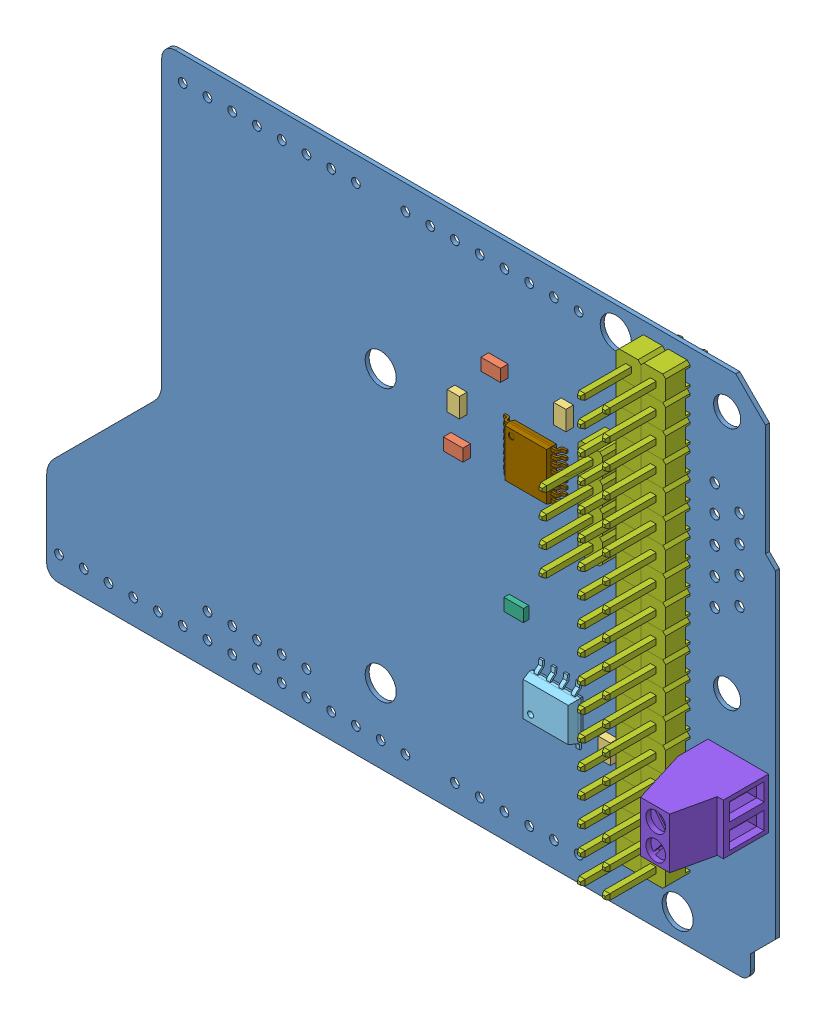
SolidWorks assembly Arduino CAN shield PCB, configuration 默认. Lengths in mm.
Overall size (74.8 53.34 11.58).
75 component instances, 9 part files, 0 mates.
Components (placement in the parent):
- Board-1: Board [默认] at (0 0 -0.4115) size (74.8 53.34 0.41)
- C1-1: C1 [默认] at origin size (2 1.25 0.78)
  - 664554168-1: 664554168 [默认] at (-19.9138 41.9098 0.0153) size (2 1.25 0.78)
    - Extruded_2-1: Extruded_2 [默认] at origin size (2 1.25 0.78)
- C2-1: C2 [默认] at origin size (1.25 2 0.78)
  - 664554032-1: 664554032 [默认] at (-23.7492 36.9318 0.0153) size (1.25 2 0.78)
    - Extruded_3-1: Extruded_3 [默认] at origin size (1.25 2 0.78)
- C3-1: C3 [默认] at origin size (1.25 2 0.78)
  - 664554032-1: 664554032 [默认] at (-12.8272 41.2498 0.0153) size (1.25 2 0.78)
    - Extruded_3-1: Extruded_3 [默认] at origin size (1.25 2 0.78)
- C4-1: C4 [默认] at origin size (2 1.25 0.78)
  - 664554304-1: 664554304 [默认] at (-21.7423 43.8149 -1.1986) size (2 1.25 0.78)
    - Extruded_4-1: Extruded_4 [默认] at origin size (2 1.25 0.78)
- C5-1: C5 [默认] at origin size (2 1.25 0.78)
  - 664554168-1: 664554168 [默认] at (-23.7742 32.8932 0.0153) size (2 1.25 0.78)
    - Extruded_2-1: Extruded_2 [默认] at origin size (2 1.25 0.78)
- C6-1: C6 [默认] at origin size (1.25 2 0.78)
  - 664554032-1: 664554032 [默认] at (-8.2548 13.8682 0.0153) size (1.25 2 0.78)
    - Extruded_3-1: Extruded_3 [默认] at origin size (1.25 2 0.78)
- CAN_1-1: CAN_1 [默认] at origin size (5.02 6.04 1.6)
  - SOP8-1: SOP8 [默认] at (-13.462 15.113 0) x (1 0 0) z (0 0 1) size (5.02 6.04 1.6)
- R1-1: R1 [默认] at origin size (2 1.26 0.55)
  - 664553896-1: 664553896 [默认] at (-17.8053 21.4885 0) size (2 1.26 0.55)
    - Extruded_5-1: Extruded_5 [默认] at origin size (2 1.26 0.55)
- GND1-1: GND1 [默认] at origin size (5.08 45.72 10.52)
  - HEADER-1: HEADER [默认] at (-2.794 49.53 0) x (0 1 0) z (1 0 0) size (2.54 10.52 2.54)
  - HEADER-2: HEADER [默认] at (-2.794 46.99 0) x (0 1 0) z (1 0 0) size (2.54 10.52 2.54)
  - HEADER-3: HEADER [默认] at (-0.254 49.53 0) x (0 1 0) z (1 0 0) size (2.54 10.52 2.54)
  - HEADER-4: HEADER [默认] at (-0.254 46.99 0) x (0 1 0) z (1 0 0) size (2.54 10.52 2.54)
  - HEADER-5: HEADER [默认] at (-2.794 44.45 0) x (0 1 0) z (1 0 0) size (2.54 10.52 2.54)
  - HEADER-6: HEADER [默认] at (-2.794 41.91 0) x (0 1 0) z (1 0 0) size (2.54 10.52 2.54)
  - HEADER-7: HEADER [默认] at (-2.794 39.37 0) x (0 1 0) z (1 0 0) size (2.54 10.52 2.54)
  - HEADER-8: HEADER [默认] at (-2.794 36.83 0) x (0 1 0) z (1 0 0) size (2.54 10.52 2.54)
  - HEADER-9: HEADER [默认] at (-0.254 44.45 0) x (0 1 0) z (1 0 0) size (2.54 10.52 2.54)
  - HEADER-10: HEADER [默认] at (-0.254 41.91 0) x (0 1 0) z (1 0 0) size (2.54 10.52 2.54)
  - HEADER-11: HEADER [默认] at (-0.254 39.37 0) x (0 1 0) z (1 0 0) size (2.54 10.52 2.54)
  - HEADER-12: HEADER [默认] at (-0.254 36.83 0) x (0 1 0) z (1 0 0) size (2.54 10.52 2.54)
  - HEADER-13: HEADER [默认] at (-2.794 34.29 0) x (0 1 0) z (1 0 0) size (2.54 10.52 2.54)
  - HEADER-14: HEADER [默认] at (-2.794 31.75 0) x (0 1 0) z (1 0 0) size (2.54 10.52 2.54)
  - HEADER-15: HEADER [默认] at (-2.794 29.21 0) x (0 1 0) z (1 0 0) size (2.54 10.52 2.54)
  - HEADER-16: HEADER [默认] at (-2.794 26.67 0) x (0 1 0) z (1 0 0) size (2.54 10.52 2.54)
  - HEADER-17: HEADER [默认] at (-0.254 34.29 0) x (0 1 0) z (1 0 0) size (2.54 10.52 2.54)
  - HEADER-18: HEADER [默认] at (-0.254 31.75 0) x (0 1 0) z (1 0 0) size (2.54 10.52 2.54)
  - HEADER-19: HEADER [默认] at (-0.254 29.21 0) x (0 1 0) z (1 0 0) size (2.54 10.52 2.54)
  - HEADER-20: HEADER [默认] at (-0.254 26.67 0) x (0 1 0) z (1 0 0) size (2.54 10.52 2.54)
  - HEADER-21: HEADER [默认] at (-2.794 24.13 0) x (0 1 0) z (1 0 0) size (2.54 10.52 2.54)
  - HEADER-22: HEADER [默认] at (-2.794 21.59 0) x (0 1 0) z (1 0 0) size (2.54 10.52 2.54)
  - HEADER-23: HEADER [默认] at (-2.794 19.05 0) x (0 1 0) z (1 0 0) size (2.54 10.52 2.54)
  - HEADER-24: HEADER [默认] at (-2.794 16.51 0) x (0 1 0) z (1 0 0) size (2.54 10.52 2.54)
  - HEADER-25: HEADER [默认] at (-0.254 24.13 0) x (0 1 0) z (1 0 0) size (2.54 10.52 2.54)
  - HEADER-26: HEADER [默认] at (-0.254 21.59 0) x (0 1 0) z (1 0 0) size (2.54 10.52 2.54)
  - HEADER-27: HEADER [默认] at (-0.254 19.05 0) x (0 1 0) z (1 0 0) size (2.54 10.52 2.54)
  - HEADER-28: HEADER [默认] at (-0.254 16.51 0) x (0 1 0) z (1 0 0) size (2.54 10.52 2.54)
  - HEADER-29: HEADER [默认] at (-2.794 13.97 0) x (0 1 0) z (1 0 0) size (2.54 10.52 2.54)
  - HEADER-30: HEADER [默认] at (-2.794 11.43 0) x (0 1 0) z (1 0 0) size (2.54 10.52 2.54)
  - HEADER-31: HEADER [默认] at (-2.794 8.89 0) x (0 1 0) z (1 0 0) size (2.54 10.52 2.54)
  - HEADER-32: HEADER [默认] at (-2.794 6.35 0) x (0 1 0) z (1 0 0) size (2.54 10.52 2.54)
  - HEADER-33: HEADER [默认] at (-0.254 13.97 0) x (0 1 0) z (1 0 0) size (2.54 10.52 2.54)
  - HEADER-34: HEADER [默认] at (-0.254 11.43 0) x (0 1 0) z (1 0 0) size (2.54 10.52 2.54)
  - HEADER-35: HEADER [默认] at (-0.254 8.89 0) x (0 1 0) z (1 0 0) size (2.54 10.52 2.54)
  - HEADER-36: HEADER [默认] at (-0.254 6.35 0) x (0 1 0) z (1 0 0) size (2.54 10.52 2.54)
- rs2322-2: rs2322 [默认] at origin size (2.54 10.16 10.52)
  - HEADER-1: HEADER [默认] at (-6.731 31.75 0) x (0 1 0) z (1 0 0) size (2.54 10.52 2.54)
  - HEADER-2: HEADER [默认] at (-6.731 34.29 0) x (0 1 0) z (1 0 0) size (2.54 10.52 2.54)
  - HEADER-3: HEADER [默认] at (-6.731 36.83 0) x (0 1 0) z (1 0 0) size (2.54 10.52 2.54)
  - HEADER-4: HEADER [默认] at (-6.731 39.37 0) x (0 1 0) z (1 0 0) size (2.54 10.52 2.54)
- CAN_bus-1: CAN_bus [默认] at origin size (6.22 5.22 10.54)
  - User_Library-Connector-2-1: User_Library-Connector-2 [默认] at (7.8106 14.224 0) x (0 1 0) z (1 0 0) size (5.22 10.54 6.22)
- RS232-1: RS232 [默认] at origin size (6.4 5 1.1)
  - User_Library-TSSOP-16-1-1: User_Library-TSSOP-16-1 [默认] at (-16.0019 35.5601 0) x (1 0 0) z (0 0 1) size (6.4 5 1.1)
- rs2322-1: rs2322 [默认] at origin size (2.54 10.16 10.52)
  - HEADER-1: HEADER [默认] at (-6.731 31.75 0) x (0 1 0) z (1 0 0) size (2.54 10.52 2.54)
  - HEADER-2: HEADER [默认] at (-6.731 34.29 0) x (0 1 0) z (1 0 0) size (2.54 10.52 2.54)
  - HEADER-3: HEADER [默认] at (-6.731 36.83 0) x (0 1 0) z (1 0 0) size (2.54 10.52 2.54)
  - HEADER-4: HEADER [默认] at (-6.731 39.37 0) x (0 1 0) z (1 0 0) size (2.54 10.52 2.54)
